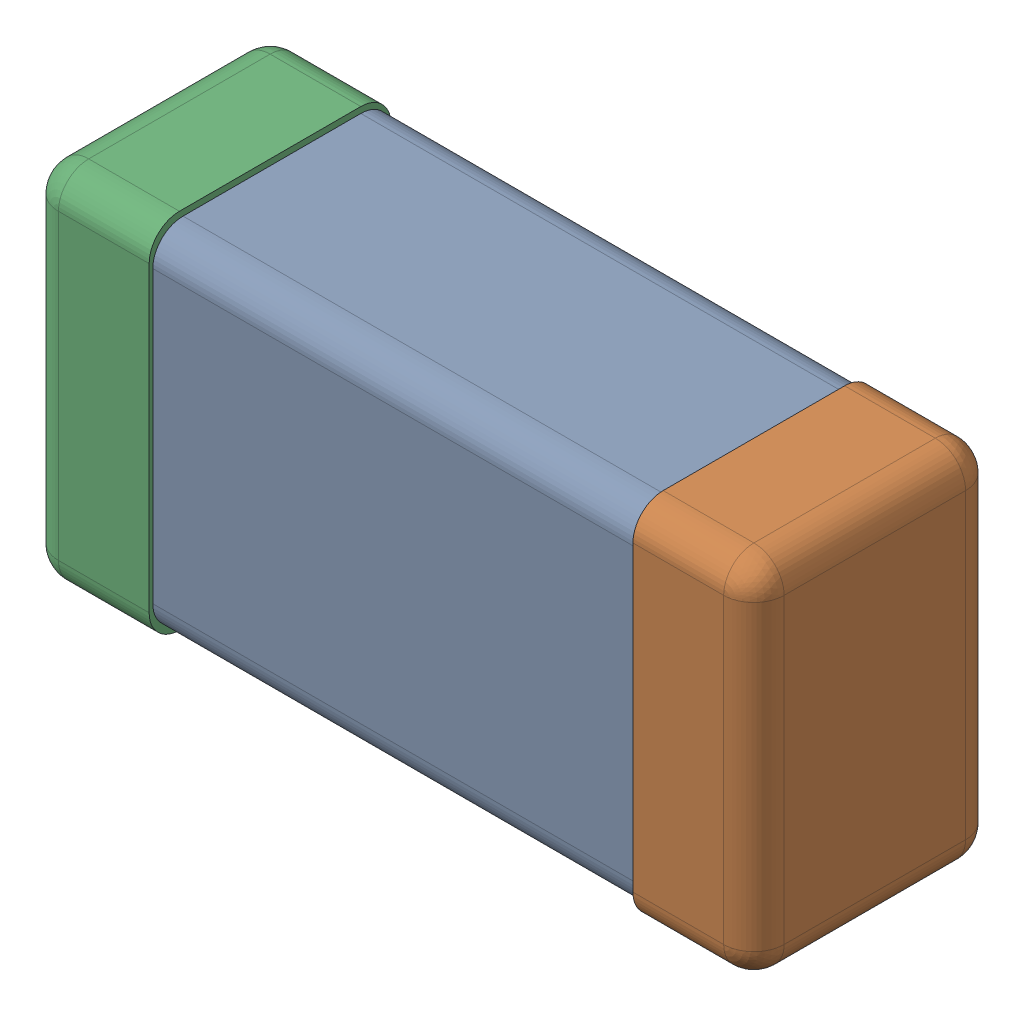
SolidWorks assembly C0201_020_12, configuration Standard. Lengths in mm.
Overall size (0.6 0.3 0.2).
4 component instances, 3 part files, 0 mates.
Components (placement in the parent):
- C0201_020_13-1: C0201_020_13 [Standard] at origin size (0.6 0.3 0.2)
  - Part 3_2-1: Part 3_2 [Standard] at (0 0 -7.3015) size (0.5 0.29 0.2)
  - Part 2_2-1: Part 2_2 [Standard] at (0 0 -7.3) size (0.1 0.3 0.2)
  - Part 1_2-1: Part 1_2 [Standard] at (0 0 -7.3) size (0.1 0.3 0.2)
